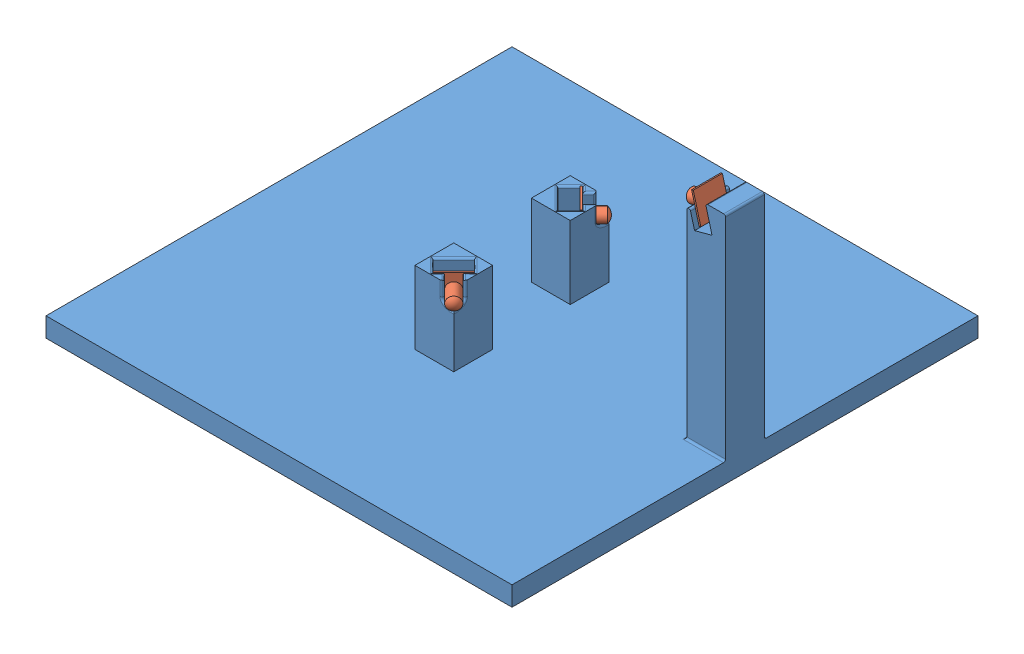
SolidWorks assembly MVP Assembly, configuration Default. Lengths in mm.
Overall size (609.6 305.39 609.6).
4 component instances, 2 part files, 9 mates.
Components (placement in the parent):
- Base-2: Base [Default] at (179.2386 202.5321 468.4042) size (609.6 304.8 609.6)
- Simple_Camera-1: Simple_Camera [Default] at (440.3772 489.5229 468.4042) x (0.258819 -0.965926 0) z (0 0 -1) size (38.1 28.96 38.1)
- Simple_Camera-2: Simple_Camera [Default] at (185.7044 304.1321 385.7384) x (0 -1 0) z (0.707107 0 0.707107) size (38.1 28.96 38.1)
- Simple_Camera-3: Simple_Camera [Default] at (185.7044 304.1321 551.07) x (0 -1 0) z (-0.707107 0 0.707107) size (38.1 28.96 38.1)
Mates (geometry in assembly coordinates):
- Coincident4: coincident anti-aligned: line of Base-2 through (173.8505 285.0821 566.1568) axis (0 1 0); line of Simple_Camera-3 through (173.8505 323.1821 566.1568) axis (0 -1 0)
- Coincident5: coincident aligned: line of Base-2 through (200.7912 285.0821 539.216) axis (0 1 0); line of Simple_Camera-3 through (200.7912 285.0821 539.216) axis (0 1 0)
- Coincident6: coincident anti-aligned: plane of Base-2 through (225.4209 285.0821 514.5864) normal (-0.707107 0 -0.707107); plane of Simple_Camera-3 through (187.3209 304.1321 552.6864) normal (0.707107 0 0.707107)
- Coincident7: coincident aligned: line of Base-2 through (173.8505 285.0821 566.1568) axis (0.707107 0 -0.707107); line of Simple_Camera-3 through (173.8505 285.0821 566.1568) axis (0.707107 0 -0.707107)
- Coincident8: coincident anti-aligned: plane of Base-2 through (225.4209 285.0821 422.2219) normal (-0.707107 0 0.707107); plane of Simple_Camera-2 through (187.3209 304.1321 384.1219) normal (0.707107 0 -0.707107)
- Coincident9: coincident anti-aligned: line of Base-2 through (173.8505 285.0821 370.6516) axis (0.707107 0 0.707107); line of Simple_Camera-2 through (200.7912 285.0821 397.5923) axis (-0.707107 0 -0.707107)
- Coincident10: coincident anti-aligned: line of Base-2 through (200.7912 285.0821 397.5923) axis (0 1 0); line of Simple_Camera-2 through (200.7912 323.1821 397.5923) axis (0 -1 0)
- Coincident18: coincident: circle of Base-2; circle of Simple_Camera-1
- Parallel3: parallel aligned: line of Base-2 through (443.4475 469.2321 443.0042) axis (0 0 1); line of Simple_Camera-1 through (443.0996 470.5304 449.3542) axis (0 0 1)
